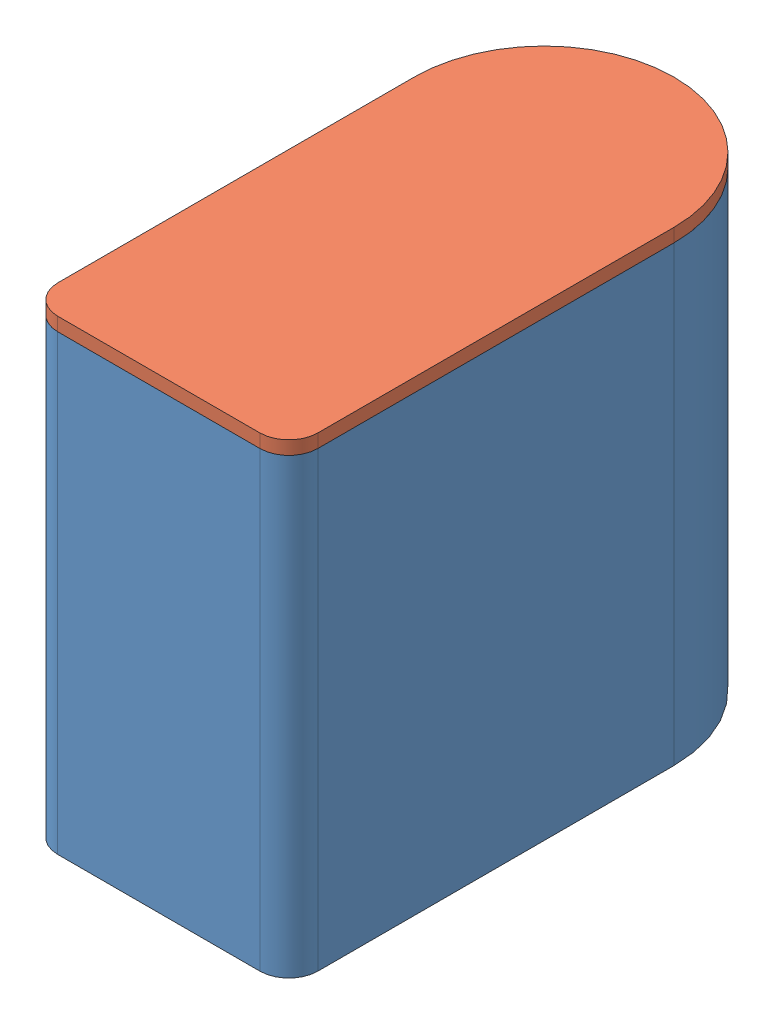
SolidWorks assembly Vanntank_assem, configuration Default. Lengths in mm.
Overall size (135 242 267.5).
2 component instances, 2 part files, 4 mates.
Components (placement in the parent):
- Vanntank-1: Vanntank [Default] at origin size (135 235 267.5)
- Vanntank_Lokk-1: Vanntank_Lokk [Default] at (0 242 0) x (-1 0 0) z (0 0 1) size (135 7 267.5)
Mates (geometry in assembly coordinates):
- Coincident2: coincident anti-aligned: plane of Vanntank-1 through (32.1334 359.9126 385.6921) normal (0.099183 0.82528 -0.555945); plane of Vanntank_Lokk-1 through (136.5675 349.4983 388.864) normal (-0.099183 -0.82528 0.555945)
- Concentric2: concentric anti-aligned: cylinder of Vanntank-1 through (78.7617 251.8555 233.6042) axis (-0.099183 -0.82528 0.555945) radius 64.5; cylinder of Vanntank_Lokk-1 through (78.7617 251.8555 233.6042) axis (0.099183 0.82528 -0.555945) radius 67.5
- Coincident3: coincident aligned: plane of Vanntank-1 through (137.0206 357.8375 401.3241) normal (0.030209 0.555945 0.83067); plane of Vanntank_Lokk-1 through (32.5865 368.2517 398.1521) normal (0.030209 0.555945 0.83067)
- Coincident4: coordinate: point of Vanntank-1
